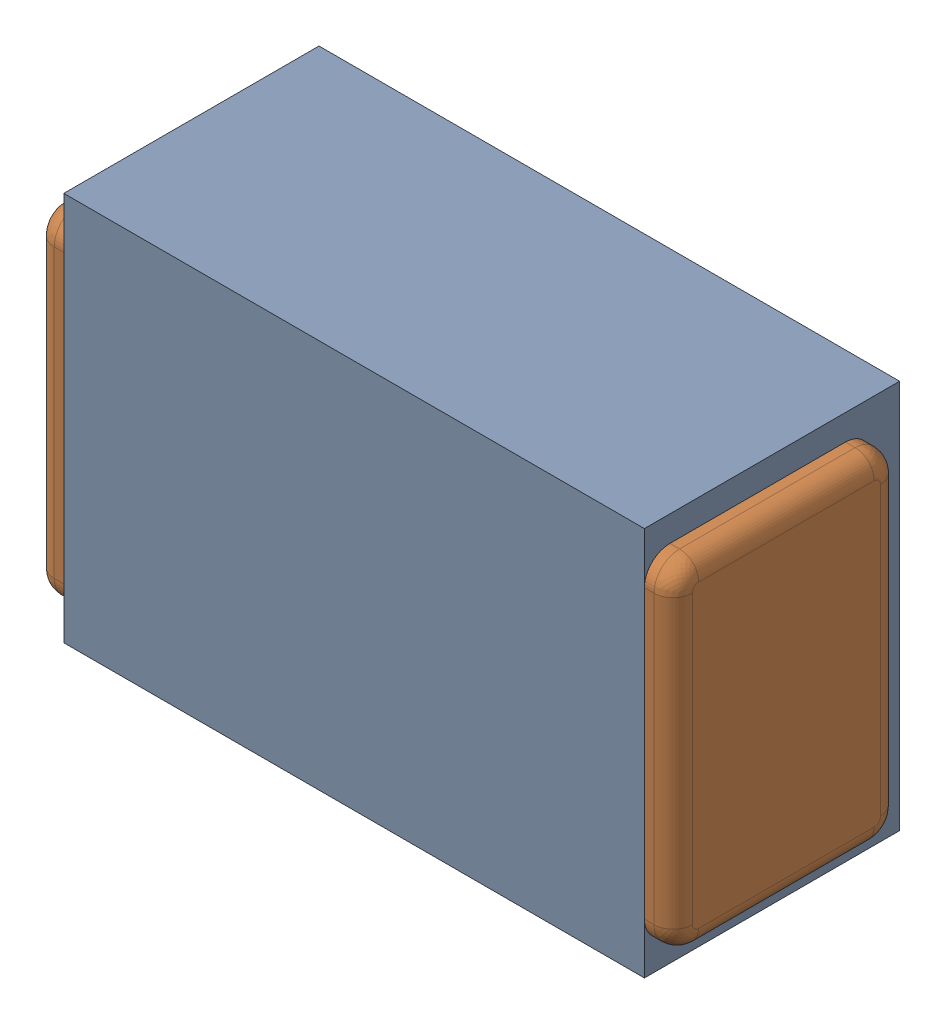
SolidWorks assembly C26, configuration Default. Lengths in mm.
Overall size (1 0.61 0.4).
3 component instances, 2 part files, 0 mates.
Components (placement in the parent):
- 1088880352-1: 1088880352 [Default] at (3.025 43.475 -2.044) size (0.91 0.61 0.4)
  - Extruded-28-1: Extruded-28 [Default] at origin size (0.91 0.61 0.4)
- C0402-1: C0402 [Default] at (3.0251 43.4749 -1.644) x (1 0 0) z (0 1 0) size (1 0.36 0.54)
